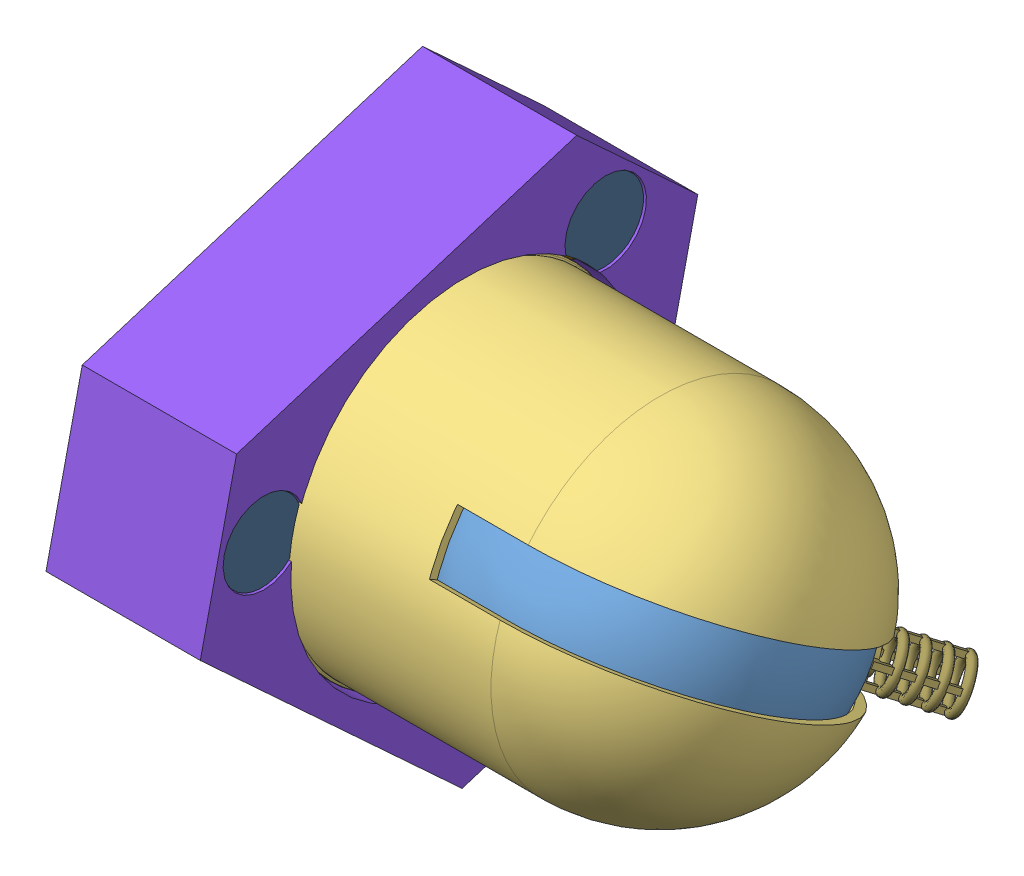
SolidWorks assembly laser turret vs 2, configuration Default. Lengths in mm.
Overall size (196.34 213.09 216.96).
23 component instances, 13 part files, 69 mates.
Components (placement in the parent):
- experiment shroud-1: experiment shroud [Default] at (18.9371 25.1803 54.4653) x (0.627284 -0.375847 -0.682095) z (0 0.875839 -0.482604) size (108.6 108.51 50)
- laserkopf-1: laserkopf [Standard] at (34.6192 33.7388 27.5196) x (0.77879 0.30273 0.5494) z (0 -0.875839 0.482604) size (33 68.5 33)
- test sheild-1: test sheild [Default] at (18.5837 42.759 44.9257) x (1 0 0) z (0 -0.482604 -0.875839) size (161.38 118.02 118)
- Nema 17HS4401-S-1: Nema 17HS4401-S [Varsayılan] at (-56.6663 77.5272 56.7951) x (0 -0.482604 -0.875839) z (0 -0.875839 0.482604) size (42 42 63.23)
- Nema 17HS4401-S-3: Nema 17HS4401-S [Varsayılan] at (-37.4663 29.6443 21.1248) x (0 -0.482604 -0.875839) z (-1 0 0) size (42 42 63.23)
- Laser Turret V2 Base-1: Laser Turret V2 Base [Default] at (-85.6663 42.759 44.9257) x (0 0.482604 0.875839) z (0 0.875839 -0.482604) size (110.01 121.16 114.29)
- battery-1: battery [Default] at (-49.1663 67.5891 31.2439) x (1 0 0) z (0 0.875839 -0.482604) size (57 30.5 14)
- stepper gear bottom-2: stepper gear bottom [Default] at (-56.6663 32.6843 81.5045) x (0.928802 -0.178842 -0.324566) z (0 0.875839 -0.482604) size (27.45 27.45 6)
- stepper gear bottom-3: stepper gear bottom [Default] at (-32.0163 34.6147 85.0078) x (0.872197 0.236068 0.42842) z (0 0.875839 -0.482604) size (27.45 27.45 6)
- stepper gear bottom-4: stepper gear bottom [Default] at (-92.6663 29.6443 21.1248) x (0 -0.348488 -0.937313) z (1 0 0) size (27.45 27.45 6)
- Laser Turret VS 2 base vs3-1: Laser Turret VS 2 base vs3 [Default] at (-108.1663 42.759 44.9257) x (0 0.297192 -0.954818) z (1 0 0) size (178.98 155 53)
- ball bearing-1: ball bearing [Default] at (18.8337 68.9028 30.5199) x (0.830959 -0.268489 -0.487258) z (0 0.875839 -0.482604) size (26 26 7.9)
- ball bearing-2: ball bearing [Default] at (18.8337 9.6961 63.144) x (1 0 0) z (0 0.875839 -0.482604) size (26 26 7.9)
- ball bearing-3: ball bearing [Default] at (-62.9663 58.3814 114.1856) x (0 0.957242 0.289288) z (1 0 0) size (26 26 7.9)
- ball bearing-4: ball bearing [Default] at (-62.9163 94.6838 -3.4976) x (0 0.994824 0.101608) z (1 0 0) size (26 26 7.9)
- ball bearing-5: ball bearing [Default] at (-55.0163 -25.3841 23.9051) x (0 0 1) z (-1 0 0) size (26 26 7.9)
- bearing color-1: bearing color [Default] at (-53.6663 58.4027 114.3088) x (0 0.993989 -0.109484) z (0 -0.109484 -0.993989) size (120 4.8 144.25)
- bearing color-2: bearing color [Default] at (-53.6663 95.0247 -3.3137) x (0 -0.591811 -0.806077) z (0 -0.806077 0.591811) size (120 4.8 144.25)
- bearing color-3: bearing color [Default] at (-53.6663 -25.1504 23.782) x (0 -0.402178 0.915562) z (0 0.915562 0.402178) size (120 4.8 144.25)
- Part3^laser turret vs 2-1: Part3^laser turret vs 2 [Default] at origin (virtual)
- bolt-1: bolt [Default] at (18.8337 60.4948 35.1529) x (-0.542831 0.405311 0.735566) z (-0.839842 -0.261973 -0.475433) size (20 23.18 23.09)
- bolt-2: bolt [Default] at (18.8337 25.0233 54.6984) x (1 0 0) z (0 -0.482604 -0.875839) size (20 23.18 23.09)
- experimental targeter-1: experimental targeter [Default] at (68.1472 13.2121 -8.6967) x (0.77879 0.30273 0.5494) z (0 -0.875839 0.482604) size (18 34 18)
Mates (geometry in assembly coordinates):
- Concentric1: concentric: circle of experiment shroud-1; cylinder of laserkopf-1 through (31.4828 25.5459 36.48) axis (0 -0.875839 0.482604) radius 1.25
- Concentric2: concentric: circle of experiment shroud-1; circle of laserkopf-1
- Coincident1: coincident: plane of experiment shroud-1 through (18.9371 28.6837 52.5349) normal (0 0.875839 -0.482604); plane of laserkopf-1 through (-9.595 33.0848 60.5222) normal (0 -0.875839 0.482604)
- Parallel2: parallel: plane of experiment shroud-1 through (18.9371 60.2139 35.1612) normal (0 0.875839 -0.482604); plane of test sheild-1 through (18.5837 42.759 44.9257) normal (0 -0.875839 0.482604)
- Symmetric1: symmetric: plane of test sheild-1 through (18.5837 61.9917 100.5504) normal (0 0.875839 -0.482604); plane of test sheild-1 through (18.5837 79.5085 90.8983) normal (0 -0.875839 0.482604); plane of assembly
- Concentric3: concentric: cylinder of test sheild-1 through (-85.6663 42.759 44.9257) axis (1 0 0) radius 55; cylinder of Laser Turret V2 Base-1 through (-77.6663 42.759 44.9257) axis (-1 0 0) radius 54.35
- Concentric4: concentric: cylinder of Nema 17HS4401-S-3 through (-100.6663 29.6443 21.1248) axis (1 0 0) radius 2.5; cylinder of Laser Turret V2 Base-1 through (-87.6663 29.6443 21.1248) axis (1 0 0) radius 4.5
- Concentric7: concentric: cylinder of Nema 17HS4401-S-3 through (-72.6663 35.7394 0.0689) axis (-1 0 0) radius 1.25; cylinder of Laser Turret V2 Base-1 through (-75.6663 35.7394 0.0689) axis (-1 0 0) radius 2
- Coincident15: coincident: plane of Nema 17HS4401-S-3 through (-79.6663 29.6443 21.1248) normal (-1 0 0); plane of Laser Turret V2 Base-1 through (-79.6663 29.6443 21.1248) normal (1 0 0)
- Parallel3: parallel: plane of experiment shroud-1 through (18.9371 25.1803 54.4653) normal (0 -0.875839 0.482604); plane of Nema 17HS4401-S-3 through (-46.9663 19.6972 46.5866) normal (0 -0.875839 0.482604)
- Concentric8: concentric: circle of Nema 17HS4401-S-1; circle of Laser Turret V2 Base-1
- Concentric9: concentric: circle of Nema 17HS4401-S-1; circle of Laser Turret V2 Base-1
- Coincident17: coincident: plane of Nema 17HS4401-S-1 through (-56.6663 40.5668 77.161) normal (0 -0.875839 0.482604); plane of Laser Turret V2 Base-1 through (-56.6663 40.5668 77.161) normal (0 0.875839 -0.482604)
- Concentric10: concentric: cylinder of Nema 17HS4401-S-1 through (-44.7496 15.259 6.4487) axis (0 0 1) radius 2.5; cylinder of ? through (-44.7496 15.259 24.4487) axis (0 0 -1) radius 2.75
- Distance1: distance = 1 mm: plane of Laser Turret V2 Base-1; plane of ? through (-44.7496 15.259 24.4487) normal (0 0 1)
- Coincident18: coincident: plane of Laser Turret V2 Base-1; plane of ? through (-11.4405 -19.297 25.4487) normal (0 0 1)
- Coincident19: coincident: plane of Laser Turret V2 Base-1; plane of ? through (-24.3906 16.3502 25.4487) normal (0 0 1)
- Concentric12: concentric: cylinder of Nema 17HS4401-S-1 through (-56.6663 22.1742 87.2957) axis (0 0.875839 -0.482604) radius 2.5; cylinder of stepper gear bottom-2 through (-56.6663 37.9393 78.6088) axis (0 -0.875839 0.482604) radius 3.05
- Distance2: distance = 1 mm: plane of Laser Turret V2 Base-1 through (-35.6663 25.7004 54.3253) normal (0 -0.875839 0.482604); plane of stepper gear bottom-3 through (-32.0163 39.8697 82.1122) normal (0 0.875839 -0.482604)
- Coincident21: coincident: plane of stepper gear bottom-2 through (-56.6663 37.9393 78.6088) normal (0 0.875839 -0.482604); plane of stepper gear bottom-3 through (-32.0163 39.8697 82.1122) normal (0 0.875839 -0.482604)
- Distance3: distance = 1 mm: plane of Laser Turret V2 Base-1; point of ?
- Concentric13: concentric: cylinder of Laser Turret V2 Base-1 through (-32.0163 51.6807 75.6041) axis (0 -0.875839 0.482604) radius 3; cylinder of stepper gear bottom-3 through (-32.0163 39.8697 82.1122) axis (0 -0.875839 0.482604) radius 3.05
- Distance4: distance = 1 mm: plane of stepper gear bottom-4 through (-86.6663 29.6443 21.1248) normal (1 0 0); plane of Laser Turret V2 Base-1 through (-85.6663 42.759 44.9257) normal (-1 0 0)
- Concentric15: concentric: cylinder of Nema 17HS4401-S-3 through (-100.6663 29.6443 21.1248) axis (1 0 0) radius 2.5; cylinder of stepper gear bottom-4 through (-86.6663 29.6443 21.1248) axis (-1 0 0) radius 3.05
- Concentric16: concentric: cylinder of test sheild-1 through (-85.6663 42.759 44.9257) axis (1 0 0) radius 58; cylinder of Laser Turret VS 2 base vs3-1 through (-98.1663 42.759 44.9257) axis (-1 0 0) radius 60
- Concentric18: concentric: cylinder of Laser Turret V2 Base-1 through (18.8337 -106.4401 127.1373) axis (0 0.875839 -0.482604) radius 13.375; cylinder of ball bearing-2 through (18.8337 16.6153 59.3314) axis (0 -0.875839 0.482604) radius 13
- Coincident22: coincident: plane of Laser Turret V2 Base-1 through (18.8337 16.6153 59.3314) normal (0 -0.875839 0.482604); circle of ball bearing-2
- Concentric19: concentric: cylinder of Laser Turret V2 Base-1 through (18.8337 -106.4401 127.1373) axis (0 0.875839 -0.482604) radius 13.375; cylinder of ball bearing-1 through (18.8337 75.822 26.7074) axis (0 -0.875839 0.482604) radius 13
- Coincident23: coincident: plane of Laser Turret V2 Base-1 through (18.8337 68.9028 30.5199) normal (0 0.875839 -0.482604); plane of ball bearing-1 through (18.8337 68.9028 30.5199) normal (0 -0.875839 0.482604)
- Concentric20: concentric: cylinder of ball bearing-2 through (30.7504 42.759 12.9257) axis (0 0 -1) radius 5; cylinder of ? through (30.7504 42.759 -2.0743) axis (0 0 1) radius 4.875
- Parallel4: parallel: plane of experiment shroud-1 through (38.1483 67.7895 24.4257) normal (-0.999992 -0.004082 0); plane of ? through (37.9004 67.2884 20.4257) normal (0.999992 0.004082 0)
- Coincident25: coincident: plane of experiment shroud-1 through (30.7504 42.759 24.4257) normal (0 0 -1); plane of ? through (30.7504 42.759 24.4257) normal (0 0 1)
- Parallel5: parallel: plane of Laser Turret VS 2 base vs3-1 through (-48.1663 42.759 44.9257) normal (1 0 0); plane of ball bearing-5 through (-62.9163 -25.3841 23.9051) normal (-1 0 0)
- Parallel6: parallel: plane of Laser Turret VS 2 base vs3-1 through (-48.1663 42.759 44.9257) normal (1 0 0); plane of ball bearing-3 through (-62.9663 58.3814 114.1856) normal (-1 0 0)
- Parallel7: parallel: plane of Laser Turret VS 2 base vs3-1 through (-48.1663 42.759 44.9257) normal (1 0 0); plane of ball bearing-4 through (-62.9163 94.6838 -3.4976) normal (-1 0 0)
- Tangent4: tangent: cylinder of test sheild-1 through (-85.6663 42.759 44.9257) axis (1 0 0) radius 58; cylinder of ball bearing-4 through (-55.0163 94.6838 -3.4976) axis (-1 0 0) radius 13
- Concentric25: concentric: cylinder of Laser Turret VS 2 base vs3-1 through (-51.1663 58.3814 114.1856) axis (-1 0 0) radius 4.9; cylinder of ball bearing-3 through (-55.0663 58.3814 114.1856) axis (-1 0 0) radius 5
- Distance6: distance = 0.2 mm: plane of Laser Turret VS 2 base vs3-1 through (-63.1663 42.759 44.9257) normal (1 0 0); plane of ball bearing-3 through (-62.9663 58.3814 114.1856) normal (-1 0 0)
- Concentric26: concentric: circle of Laser Turret VS 2 base vs3-1; cylinder of ball bearing-4 through (-55.0163 94.6838 -3.4976) axis (-1 0 0) radius 5
- Distance7: distance = 0.25 mm: plane of Laser Turret VS 2 base vs3-1 through (-63.1663 42.759 44.9257) normal (1 0 0); plane of ball bearing-4 through (-62.9163 94.6838 -3.4976) normal (-1 0 0)
- Concentric27: concentric: cylinder of Laser Turret VS 2 base vs3-1 through (-51.1663 -25.3841 23.9051) axis (-1 0 0) radius 4.9; cylinder of ball bearing-5 through (-62.9163 -25.3841 23.9051) axis (1 0 0) radius 5
- Distance8: distance = 0.25 mm: plane of Laser Turret VS 2 base vs3-1 through (-63.1663 42.759 44.9257) normal (1 0 0); plane of ball bearing-5 through (-62.9163 -25.3841 23.9051) normal (-1 0 0)
- Coincident31: coincident: plane of Laser Turret VS 2 base vs3-1 through (-51.1663 58.3814 114.1856) normal (1 0 0); circle of bearing color-1
- Concentric29: concentric: cylinder of Laser Turret VS 2 base vs3-1 through (-63.1663 94.9288 -3.2336) axis (1 0 0) radius 14; cylinder of bearing color-2 through (-51.1663 94.9288 -3.2336) axis (-1 0 0) radius 13.7
- Coincident32: coincident: plane of Laser Turret VS 2 base vs3-1 through (-51.1663 94.6838 -3.4976) normal (1 0 0); plane of bearing color-2 through (-51.1663 95.0247 -3.3137) normal (-1 0 0)
- Concentric30: concentric: cylinder of test sheild-1 through (-85.6663 42.759 44.9257) axis (1 0 0) radius 58; cylinder of bearing color-2 through (-51.1663 42.759 44.9257) axis (-1 0 0) radius 60
- Coincident33: coincident: plane of Laser Turret VS 2 base vs3-1 through (-51.1663 -25.3841 23.9051) normal (1 0 0); circle of bearing color-3
- Concentric31: concentric: cylinder of Laser Turret VS 2 base vs3-1 through (-63.1663 -25.033 23.825) axis (1 0 0) radius 14; cylinder of bearing color-3 through (-51.1663 -25.033 23.825) axis (-1 0 0) radius 13.7
- Concentric32: concentric: cylinder of test sheild-1 through (-85.6663 42.759 44.9257) axis (1 0 0) radius 58; cylinder of bearing color-3 through (-51.1663 42.759 44.9257) axis (-1 0 0) radius 60
- Concentric33: concentric: cylinder of Laser Turret VS 2 base vs3-1 through (-63.1663 58.3814 114.1856) axis (1 0 0) radius 14; cylinder of bearing color-1 through (-51.1663 58.3814 114.1856) axis (-1 0 0) radius 13.7
- Concentric34: concentric: cylinder of ball bearing-1 through (18.8337 75.822 26.7074) axis (0 -0.875839 0.482604) radius 5; cylinder of bolt-1 through (18.8337 75.822 26.7074) axis (0 -0.875839 0.482604) radius 4.8
- Coincident34: coincident: plane of ball bearing-1 through (18.8337 75.822 26.7074) normal (0 0.875839 -0.482604); plane of bolt-1 through (18.8337 75.822 26.7074) normal (0 -0.875839 0.482604)
- Concentric35: concentric: cylinder of ball bearing-2 through (18.8337 16.6153 59.3314) axis (0 -0.875839 0.482604) radius 5; cylinder of bolt-2 through (18.8337 9.6961 63.144) axis (0 0.875839 -0.482604) radius 4.8
- Coincident36: coincident: plane of ball bearing-2 through (18.8337 9.6961 63.144) normal (0 -0.875839 0.482604); plane of bolt-2 through (18.8337 9.6961 63.144) normal (0 0.875839 -0.482604)
- Concentric36: concentric: cylinder of experiment shroud-1 through (18.8337 64.655 32.8606) axis (0 -0.875839 0.482604) radius 5; cylinder of Laser Turret V2 Base-1 through (18.8337 68.9028 30.5199) axis (0 0.875839 -0.482604) radius 13.375
- Coincident38: coincident: plane of test sheild-1 through (-85.6663 42.759 44.9257) normal (-1 0 0); plane of Laser Turret V2 Base-1 through (-85.6663 42.759 44.9257) normal (-1 0 0)
- Distance11: distance = 1.5 mm: plane of Laser Turret V2 Base-1 through (-85.6663 42.759 44.9257) normal (-1 0 0); plane of Laser Turret VS 2 base vs3-1 through (-87.1663 42.759 44.9257) normal (1 0 0)
- Coincident41: coincident: plane of Laser Turret V2 Base-1 through (42.4031 56.7305 11.5375) normal (0 0.875839 -0.482604); plane of battery-1 through (-49.1663 67.5891 31.2439) normal (0 -0.875839 0.482604)
- Symmetric2: symmetric: plane of Laser Turret V2 Base-1 through (-2.6663 53.6176 64.632) normal (0 -0.482604 -0.875839); plane of Laser Turret V2 Base-1 through (-2.6663 31.9005 25.2193) normal (0 0.482604 0.875839); plane of assembly
- Coincident42: coincident: plane of Laser Turret V2 Base-1 through (-77.6663 42.759 44.9257) normal (1 0 0); plane of battery-1 through (-77.6663 87.2105 37.8439) normal (-1 0 0)
- Coincident43: coincident: circle of Laser Turret VS 2 base vs3-1; plane of ? through (-102.1663 42.759 44.9257) normal (-1 0 0)
- Concentric37: concentric: cylinder of Laser Turret VS 2 base vs3-1 through (-94.1663 42.759 44.9257) axis (-1 0 0) radius 13.125; cylinder of ? through (-102.1663 42.759 44.9257) axis (1 0 0) radius 13
- Concentric38: concentric: cylinder of experiment shroud-1 through (54.6299 21.3112 6.0017) axis (-0.627284 0.375847 0.682095) radius 4; cylinder of experimental targeter-1 through (47.7604 25.4271 13.4714) axis (0.627284 -0.375847 -0.682095) radius 4
- Tangent5: tangent: torus of experiment shroud-1; circle of experimental targeter-1
- Parallel8: parallel: plane of experiment shroud-1 through (24.778 66.8635 36.8686) normal (0.77879 0.30273 0.5494); plane of experimental targeter-1 through (54.8121 27.6643 4.0629) normal (0.77879 0.30273 0.5494)
- InPlace1: in place: plane of Laser Turret VS 2 base vs3-1 through (-96.1663 42.759 44.9257) normal (-1 0 0); plane of ? through (-96.1663 0 0) normal (-1 0 0); moOrthogonalPlaneRef_w of Laser Turret VS 2 base vs3-1 through (-96.1663 42.759 44.9257) normal (-1 0 0); plane of ? through (-96.1663 0 0) normal (0 1 0); plane of Laser Turret VS 2 base vs3-1 through (-96.1663 42.759 44.9257) normal (-1 0 0); plane of ? through (-96.1663 0 0) normal (0 0 1); plane of Laser Turret VS 2 base vs3-1 through (-96.1663 42.759 44.9257) normal (-1 0 0); unknown of ?
- Coincident44: coincident: plane of Laser Turret VS 2 base vs3-1; plane of ?
- Coincident45: coincident: moOrthogonalPlaneRef_w of Laser Turret VS 2 base vs3-1 through (-96.1663 42.759 44.9257) normal (0 0.954818 0.297192); plane of ? through (-96.1663 42.759 44.9257) normal (0 0.954818 0.297192)
- Coincident46: coincident: moOrthogonalPlaneRef_w of Laser Turret VS 2 base vs3-1 through (-96.1663 42.759 44.9257) normal (0 0.297192 -0.954818); plane of ? through (-96.1663 42.759 44.9257) normal (0 -0.297192 0.954818)
